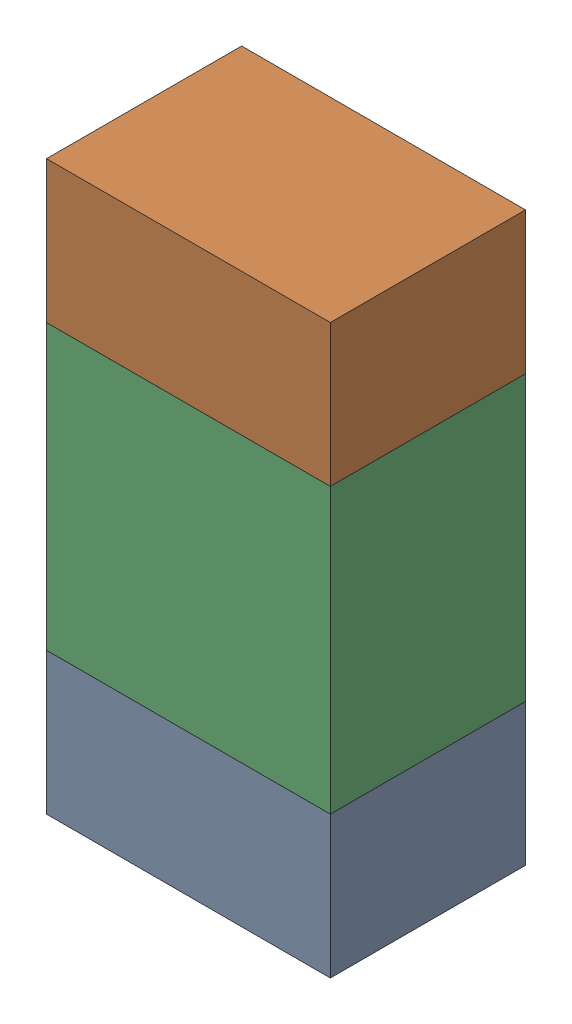
SolidWorks assembly R31, configuration ﾃﾞﾌｫﾙﾄ. Lengths in mm.
Overall size (0.8 1.6 0.55).
6 component instances, 2 part files, 0 mates.
Components (placement in the parent):
- 689261784-1: 689261784 [ﾃﾞﾌｫﾙﾄ] at (34.6076 21.9426 -1.7503) size (0.8 0.4 0.55)
  - Extruded_34-1: Extruded_34 [ﾃﾞﾌｫﾙﾄ] at origin size (0.8 0.4 0.55)
- 689261784-2: 689261784 [ﾃﾞﾌｫﾙﾄ] at (34.6076 23.1426 -1.7503) size (0.8 0.4 0.55)
  - Extruded_34-1: Extruded_34 [ﾃﾞﾌｫﾙﾄ] at origin size (0.8 0.4 0.55)
- 689261648-1: 689261648 [ﾃﾞﾌｫﾙﾄ] at (34.6076 22.5425 -1.7503) size (0.8 0.8 0.55)
  - Extruded_33-1: Extruded_33 [ﾃﾞﾌｫﾙﾄ] at origin size (0.8 0.8 0.55)
